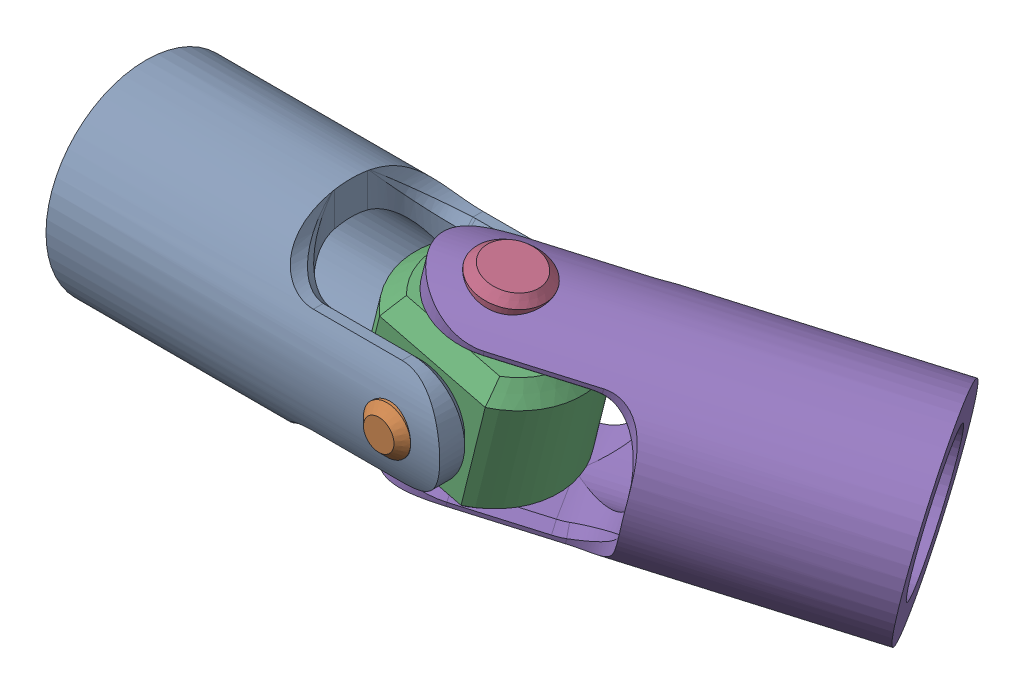
SolidWorks assembly Assem3, configuration Default. Lengths in mm.
Overall size (249.5 108.28 134.85).
5 component instances, 5 part files, 10 mates.
Components (placement in the parent):
- Small-Hole-Fork-Base-1: Small-Hole-Fork-Base [Default] at origin size (142 72 72)
- Small-Pin-1: Small-Pin [Default] at (123 0 0) x (0.935017 0.354604 0) z (0 0 1) size (17 17 78)
- Center-Block-1: Center-Block [Default] at (123 0 0) x (-0.970296 0.241922 0) z (0 0 1) size (62 48 48)
- Large-Pin-1: Large-Pin [Default] at (123 0 0) x (0.970296 -0.241922 0) z (0 0 1) size (25 78 25)
- Large-Hole-Fork-1: Large-Hole-Fork [Default] at (222.8047 -24.8841 -61.8046) x (-0.831706 0.207368 0.515038) z (0.241922 0.970296 0) size (142 72 72)
Mates (geometry in assembly coordinates):
- Concentric1: concentric aligned: cylinder of Small-Hole-Fork-Base-1 through (123 0 -36) axis (0 0 1) radius 8.5; cylinder of Center-Block-1 through (123 0 -24) axis (0 0 1) radius 8.5
- Concentric2: concentric anti-aligned: cylinder of Small-Hole-Fork-Base-1 through (123 0 -36) axis (0 0 1) radius 8.5; cylinder of Small-Pin-1 through (123 0 39) axis (0 0 -1) radius 8.5
- Width1: width anti-aligned: plane of Center-Block-1 through (136.2325 -28.0339 24) normal (0 0 1); plane of Center-Block-1 through (136.2325 -28.0339 -24) normal (0 0 -1); plane of Small-Pin-1 through (123 0 -39) normal (0 0 -1); plane of Small-Pin-1 through (123 0 39) normal (0 0 1)
- Concentric3: concentric anti-aligned: cylinder of Small-Pin-1 through (123 0 39) axis (0 0 -1) radius 8.5; cylinder of Large-Pin-1 through (123 0 -12.5) axis (0 0 1) radius 8.5
- Concentric4: concentric anti-aligned: cylinder of Center-Block-1 through (117.1939 -23.2871 0) axis (0.241922 0.970296 0) radius 12.5; cylinder of Large-Pin-1 through (132.435 37.8415 0) axis (-0.241922 -0.970296 0) radius 12.5
- Concentric5: concentric anti-aligned: cylinder of Large-Pin-1 through (132.435 37.8415 0) axis (-0.241922 -0.970296 0) radius 12.5; cylinder of Large-Hole-Fork-1 through (114.2908 -34.9306 0) axis (0.241922 0.970296 0) radius 12.5
- Coincident1: coincident anti-aligned: plane of Center-Block-1 through (117.1939 -23.2871 0) normal (-0.241922 -0.970296 0); plane of Large-Hole-Fork-1 through (80.9057 -14.2394 -19.5272) normal (0.241922 0.970296 0)
- Coincident2: coincident anti-aligned: plane of Small-Hole-Fork-Base-1 through (142 -36 24) normal (0 0 -1); plane of Center-Block-1 through (136.2325 -28.0339 24) normal (0 0 1)
- Angle1: planar angle = 0.244346 rad aligned: line of Small-Hole-Fork-Base-1 through (91 19 30.5778) axis (1 0 0); line of Center-Block-1 through (111.9721 27.4843 18) axis (0.970296 -0.241922 0)
- Angle2: planar angle = 0.541052 rad anti-aligned: line of Center-Block-1 through (108.316 22.2122 -24) axis (0.970296 -0.241922 0); line of Large-Hole-Fork-1 through (145.514 23.7546 -35.3389) axis (-0.831706 0.207368 0.515038)
